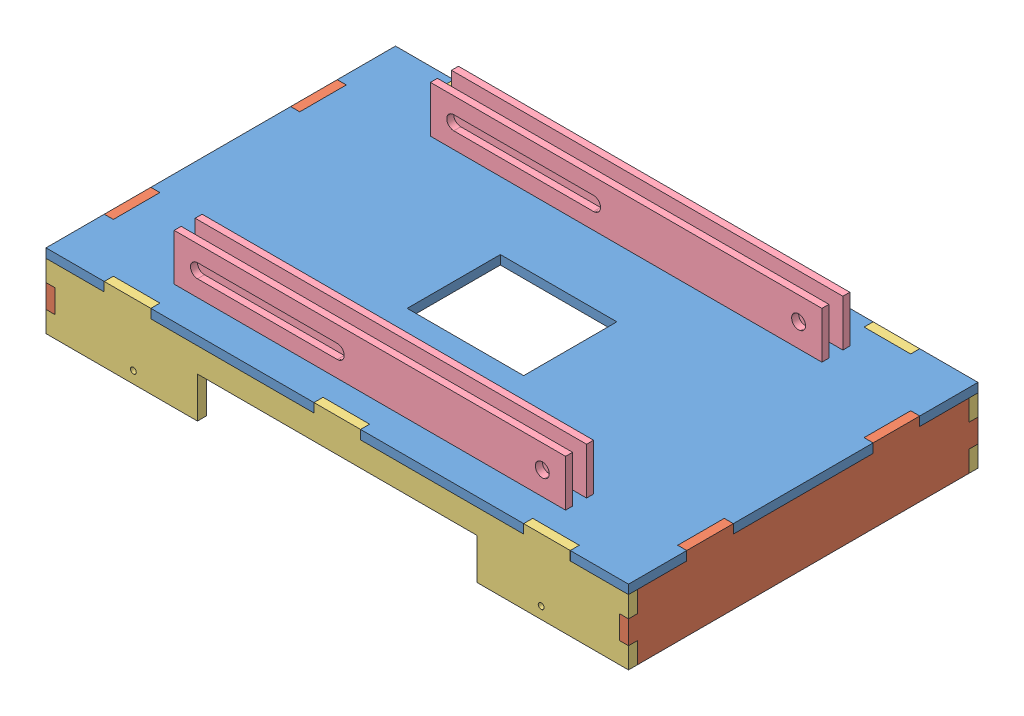
SolidWorks assembly Baseplate Assembly, configuration Default. Lengths in mm.
Overall size (250 51.9 150).
9 component instances, 4 part files, 24 mates.
Components (placement in the parent):
- Baseplate-1: Baseplate [Default] at (65.4966 128.7181 206.065) size (250 3.9 150)
- Baseplate Short Side-1: Baseplate Short Side [Default] at (186.5966 114.7181 206.065) x (0 0 -1) z (0 -1 0) size (150 3.9 31.9)
- Baseplate Wide Side-1: Baseplate Wide Side [Default] at (65.4966 114.7181 281.065) x (-1 0 0) z (0 -1 0) size (250 3.9 31.9)
- Lift Axle Track-1: Lift Axle Track [Default] at (149.4966 132.6181 267.065) x (-1 0 0) z (0 -1 0) size (168 3 23.9)
- Baseplate Short Side-2: Baseplate Short Side [Default] at (-55.6034 114.7181 206.065) x (0 0 1) z (0 -1 0) size (150 3.9 31.9)
- Baseplate Wide Side-2: Baseplate Wide Side [Default] at (65.4966 114.7181 134.965) x (-1 0 0) z (0 -1 0) size (250 3.9 31.9)
- Lift Axle Track-2: Lift Axle Track [Default] at (149.4966 132.6181 157.065) x (-1 0 0) z (0 -1 0) size (168 3 23.9)
- Lift Axle Track-3: Lift Axle Track [Default] at (149.4966 132.6181 258.065) x (-1 0 0) z (0 -1 0) size (168 3 23.9)
- Lift Axle Track-4: Lift Axle Track [Default] at (149.4966 132.6181 148.065) x (-1 0 0) z (0 -1 0) size (168 3 23.9)
Mates (geometry in assembly coordinates):
- Coincident1: coincident aligned: plane of Baseplate-1 through (65.4966 132.6181 206.065) normal (0 1 0); plane of Baseplate Wide Side-1 through (65.4966 132.6181 277.165) normal (0 1 0)
- Coincident3: coincident aligned: plane of Baseplate-1 through (190.4966 132.6181 131.065) normal (1 0 0); plane of Baseplate Wide Side-1 through (190.4966 114.7181 277.165) normal (1 0 0)
- Coincident4: coincident aligned: plane of Baseplate-1 through (65.4966 128.7181 206.065) normal (0 -1 0); plane of Lift Axle Track-1 through (0.4966 128.7181 264.065) normal (0 -1 0)
- Coincident5: coincident anti-aligned: plane of Baseplate-1 through (130.4966 132.6181 264.065) normal (-1 0 0); plane of Lift Axle Track-1 through (130.4966 132.6181 264.065) normal (1 0 0)
- Coincident6: coincident anti-aligned: plane of Baseplate-1 through (130.4966 132.6181 267.065) normal (0 0 -1); plane of Lift Axle Track-1 through (149.4966 132.6181 267.065) normal (0 0 1)
- Coincident7: coincident aligned: plane of Baseplate-1 through (65.4966 132.6181 206.065) normal (0 1 0); plane of Baseplate Short Side-1 through (190.4966 132.6181 156.065) normal (0 1 0)
- Coincident8: coincident aligned: plane of Baseplate-1 through (190.4966 132.6181 131.065) normal (1 0 0); plane of Baseplate Short Side-1 through (190.4966 114.7181 206.065) normal (1 0 0)
- Coincident9: coincident anti-aligned: plane of Baseplate-1 through (190.4966 132.6181 256.065) normal (0 0 -1); plane of Baseplate Short Side-1 through (190.4966 128.7181 256.065) normal (0 0 1)
- Coincident10: coincident anti-aligned: plane of Baseplate-1 through (-55.6034 132.6181 256.065) normal (-1 0 0); plane of Baseplate Short Side-2 through (-55.6034 114.7181 206.065) normal (1 0 0)
- Coincident11: coincident aligned: plane of Baseplate-1 through (65.4966 132.6181 206.065) normal (0 1 0); plane of Baseplate Short Side-2 through (-59.5034 132.6181 156.065) normal (0 1 0)
- Coincident12: coincident anti-aligned: plane of Baseplate-1 through (-59.5034 132.6181 256.065) normal (0 0 -1); plane of Baseplate Short Side-2 through (-59.5034 128.7181 256.065) normal (0 0 1)
- Coincident13: coincident aligned: plane of Baseplate-1 through (65.4966 128.7181 206.065) normal (0 -1 0); plane of Lift Axle Track-4 through (130.4966 128.7181 145.065) normal (0 -1 0)
- Coincident14: coincident aligned: plane of Baseplate-1 through (65.4966 128.7181 206.065) normal (0 -1 0); plane of Lift Axle Track-2 through (130.4966 128.7181 154.065) normal (0 -1 0)
- Coincident15: coincident aligned: plane of Baseplate-1 through (65.4966 128.7181 206.065) normal (0 -1 0); plane of Lift Axle Track-3 through (130.4966 128.7181 255.065) normal (0 -1 0)
- Coincident16: coincident anti-aligned: plane of Baseplate-1 through (130.4966 132.6181 258.065) normal (0 0 -1); plane of Lift Axle Track-3 through (149.4966 132.6181 258.065) normal (0 0 1)
- Coincident17: coincident anti-aligned: plane of Baseplate-1 through (130.4966 132.6181 154.065) normal (0 0 1); plane of Lift Axle Track-2 through (149.4966 132.6181 154.065) normal (0 0 -1)
- Coincident18: coincident anti-aligned: plane of Baseplate-1 through (130.4966 132.6181 145.065) normal (0 0 1); plane of Lift Axle Track-4 through (149.4966 132.6181 145.065) normal (0 0 -1)
- Coincident19: coincident anti-aligned: plane of Baseplate-1 through (130.4966 132.6181 258.065) normal (-1 0 0); plane of Lift Axle Track-3 through (130.4966 132.6181 255.065) normal (1 0 0)
- Coincident20: coincident anti-aligned: plane of Baseplate-1 through (110.4966 132.6181 154.065) normal (1 0 0); plane of Lift Axle Track-2 through (110.4966 132.6181 154.065) normal (-1 0 0)
- Coincident21: coincident anti-aligned: plane of Baseplate-1 through (130.4966 132.6181 148.065) normal (-1 0 0); plane of Lift Axle Track-4 through (130.4966 132.6181 145.065) normal (1 0 0)
- Coincident22: coincident aligned: plane of Baseplate-1 through (65.4966 132.6181 206.065) normal (0 1 0); plane of Baseplate Wide Side-2 through (65.4966 132.6181 131.065) normal (0 1 0)
- Coincident25: coincident anti-aligned: plane of Baseplate-1 through (75.4966 132.6181 134.965) normal (-1 0 0); plane of Baseplate Wide Side-2 through (75.4966 114.7181 131.065) normal (1 0 0)
- Coincident26: coincident aligned: plane of Baseplate-1 through (75.4966 132.6181 281.065) normal (0 0 1); plane of Baseplate Wide Side-1 through (65.4966 114.7181 281.065) normal (0 0 1)
- Coincident27: coincident aligned: plane of Baseplate-1 through (165.4966 132.6181 131.065) normal (0 0 -1); plane of Baseplate Wide Side-2 through (65.4966 114.7181 131.065) normal (0 0 -1)
